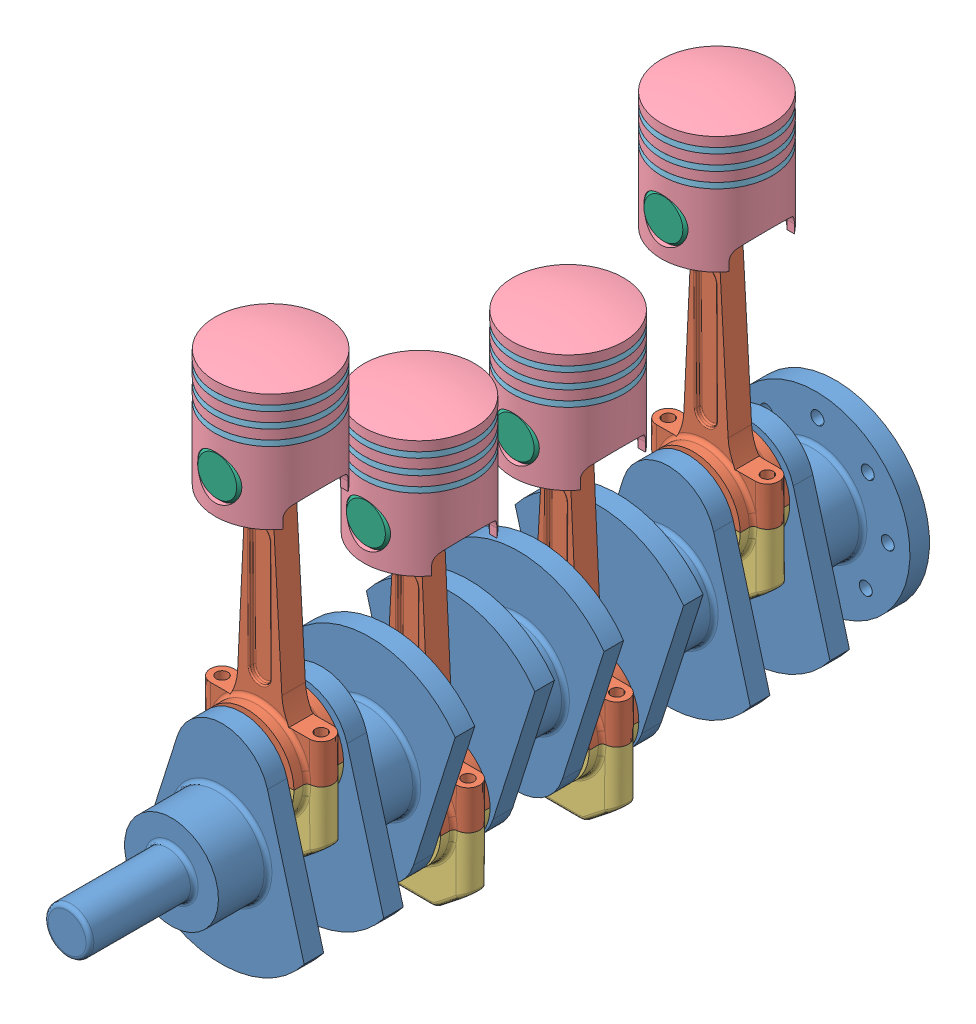
SolidWorks assembly Engine 2003083, configuration Default. Lengths in mm.
Overall size (147.06 418.41 589).
29 component instances, 6 part files, 66 mates.
Components (placement in the parent):
- Crankshaft-1: Crankshaft [Default] at (0 0 456) x (-0.999814 0.019293 0) z (0 0 1) size (144 160 589)
- Connecting rod-1: Connecting rod [Default] at (0 245.19 433) x (0.999991 0.004219 0) z (0 0 1) size (94 223.7 38)
- Connecting rod cap-1: Connecting rod cap [Default] at (0.8489 43.9918 433) x (-0.999991 -0.004219 0) z (0 0 1) size (94 60 38)
- Piston-1: Piston [Default] at (0 219.2199 433) size (85 95 85)
- Piston ring-1: Piston ring [Default] at (0 297.6199 433) size (85 4.3 85)
- Piston Pin-1: Piston Pin [Default] at (0 245.19 433) size (33.8 33.8 82)
- Piston ring-2: Piston ring [Default] at (0 286.0199 433) x (0.546944 0 -0.837169) z (0.837169 0 0.546944) size (85 4.3 85)
- Piston ring-4: Piston ring [Default] at (0 274.4199 433) x (0.546944 0 -0.837169) z (0.837169 0 0.546944) size (85 4.3 85)
- Piston-2: Piston [Default] at (0 131.2362 319) size (85 95 85)
- Piston ring-6: Piston ring [Default] at (0 209.6362 319) x (0.941458 0 -0.337131) z (0.337131 0 0.941458) size (85 4.3 85)
- Piston ring-7: Piston ring [Default] at (0 198.0362 319) x (0.23269 0 -0.972551) z (0.972551 0 0.23269) size (85 4.3 85)
- Piston ring-8: Piston ring [Default] at (0 186.4362 319) x (0.23269 0 -0.972551) z (0.972551 0 0.23269) size (85 4.3 85)
- Piston Pin-2: Piston Pin [Default] at (0 157.2064 319) x (0.216826 -0.97621 0) z (0 0 1) size (33.8 33.8 82)
- Connecting rod-2: Connecting rod [Default] at (0 157.2064 319) x (0.999991 -0.004219 0) z (0 0 1) size (94 223.7 38)
- Connecting rod cap-2: Connecting rod cap [Default] at (-0.8489 -43.9918 319) x (-0.999991 0.004219 0) z (0 0 1) size (94 60 38)
- Piston-4: Piston [Default] at (0 131.2362 205) x (-1 0 0) z (0 0 -1) size (85 95 85)
- Piston ring-12: Piston ring [Default] at (0 209.6362 205) x (0.790546 0 -0.612403) z (0.612403 0 0.790546) size (85 4.3 85)
- Piston ring-13: Piston ring [Default] at (0 198.0362 205) x (-0.0803 0 -0.996771) z (0.996771 0 -0.0803) size (85 4.3 85)
- Piston ring-14: Piston ring [Default] at (0 186.4362 205) x (-0.0803 0 -0.996771) z (0.996771 0 -0.0803) size (85 4.3 85)
- Piston Pin-4: Piston Pin [Default] at (0 157.2064 205) x (-0.34202 0.939693 0) z (0 0 -1) size (33.8 33.8 82)
- Connecting rod-4: Connecting rod [Default] at (0 157.2064 205) x (-0.999991 0.004219 0) z (0 0 -1) size (94 223.7 38)
- Connecting rod cap-4: Connecting rod cap [Default] at (-0.8489 -43.9918 205) x (0.999991 -0.004219 0) z (0 0 -1) size (94 60 38)
- Piston-6: Piston [Default] at (0 219.2199 91) x (-1 0 0) z (0 0 -1) size (85 95 85)
- Piston ring-18: Piston ring [Default] at (0 297.6199 91) x (0.6 0 -0.8) z (0.8 0 0.6) size (85 4.3 85)
- Piston ring-19: Piston ring [Default] at (0 286.0199 91) x (-0.341569 0 -0.939857) z (0.939857 0 -0.341569) size (85 4.3 85)
- Piston ring-20: Piston ring [Default] at (0 274.4199 91) x (-0.341569 0 -0.939857) z (0.939857 0 -0.341569) size (85 4.3 85)
- Piston Pin-6: Piston Pin [Default] at (0 245.19 91) x (-0.5 0.866025 0) z (0 0 -1) size (33.8 33.8 82)
- Connecting rod-6: Connecting rod [Default] at (0 245.19 91) x (-0.999991 -0.004219 0) z (0 0 -1) size (94 223.7 38)
- Connecting rod cap-6: Connecting rod cap [Default] at (0.8489 43.9918 91) x (0.999991 0.004219 0) z (0 0 -1) size (94 60 38)
Mates (geometry in assembly coordinates):
- Concentric1: concentric anti-aligned: cylinder of Crankshaft-1 through (0 0 589) axis (0 0 -1) radius 17.5
- Coincident1: coincident: plane of Crankshaft-1 through (0 0 589) normal (0 0 1)
- Coincident2: coincident aligned: plane of Piston-1 through (0 219.2199 433) normal (0 0 1); plane of Piston Pin-1 through (0 245.19 433) normal (0 0 1)
- Concentric2: concentric anti-aligned: cylinder of Piston-1 through (0 245.19 390.5) axis (0 0 1) radius 16.9; cylinder of Piston Pin-1 through (0 245.19 474) axis (0 0 -1) radius 16.9
- Concentric3: concentric aligned: cylinder of Piston-1 through (0 309.2199 433) axis (0 -1 0) radius 42.5; cylinder of Piston ring-1 through (0 301.9199 433) axis (0 -1 0) radius 42.5
- Coincident3: coincident anti-aligned: plane of Piston-1 through (0 297.6199 433) normal (0 1 0); plane of Piston ring-1 through (0 297.6199 433) normal (0 -1 0)
- Concentric4: concentric anti-aligned: cylinder of Piston-1 through (0 286.0199 433) axis (0 1 0) radius 39.5; cylinder of Piston ring-2 through (0 290.3199 433) axis (0 -1 0) radius 42.5
- Coincident4: coincident anti-aligned: plane of Piston-1 through (0 286.0199 433) normal (0 1 0); plane of Piston ring-2 through (0 286.0199 433) normal (0 -1 0)
- Concentric5: concentric anti-aligned: cylinder of Piston-1 through (0 274.4199 433) axis (0 1 0) radius 39.5; cylinder of Piston ring-4 through (0 278.7199 433) axis (0 -1 0) radius 42.5
- Coincident5: coincident anti-aligned: plane of Piston-1 through (0 274.4199 433) normal (0 1 0); plane of Piston ring-4 through (0 274.4199 433) normal (0 -1 0)
- Coincident6: coincident aligned: plane of Connecting rod-1 through (0 245.19 433) normal (0 0 1); plane of Piston-1 through (0 219.2199 433) normal (0 0 1)
- Concentric6: concentric aligned: cylinder of Connecting rod-1 through (0 245.19 452) axis (0 0 -1) radius 16.9; cylinder of Piston Pin-1 through (0 245.19 474) axis (0 0 -1) radius 16.9
- Concentric7: concentric aligned: cylinder of Connecting rod-1 through (38.8486 44.1521 433) axis (-0.004219 0.999991 0) radius 4.5; cylinder of Connecting rod cap-1 through (39.1017 -15.8473 433) axis (-0.004219 0.999991 0) radius 4.5
- Concentric8: concentric aligned: cylinder of Connecting rod-1 through (-37.1508 43.8315 433) axis (-0.004219 0.999991 0) radius 4.5; cylinder of Connecting rod cap-1 through (-36.8976 -16.168 433) axis (-0.004219 0.999991 0) radius 4.5
- Coincident7: coincident anti-aligned: plane of Connecting rod-1 through (0.8489 43.9918 452) normal (0.004219 -0.999991 0); plane of Connecting rod cap-1 through (36.8486 44.1437 452) normal (-0.004219 0.999991 0)
- Width1: width anti-aligned: plane of Crankshaft-1 through (0 0 410) normal (0 0 1); plane of Crankshaft-1 through (0 0 456) normal (0 0 -1); plane of Connecting rod-1 through (0 245.19 424) normal (0 0 -1); plane of Connecting rod-1 through (0 245.19 442) normal (0 0 1)
- Concentric9: concentric anti-aligned: cylinder of Crankshaft-1 through (0.8489 43.9918 410) axis (0 0 1) radius 27; cylinder of Connecting rod-1 through (0.8489 43.9918 452) axis (0 0 -1) radius 27
- Concentric10: concentric anti-aligned: cylinder of Piston-1 through (0 309.2199 433) axis (0 -1 0) radius 42.5
- Coincident9: coincident aligned: plane of Piston-2 through (0 131.2362 319) normal (0 0 1); plane of Piston Pin-2 through (0 157.2064 319) normal (0 0 1)
- Concentric11: concentric anti-aligned: cylinder of Piston-2 through (0 157.2064 276.5) axis (0 0 1) radius 16.9; cylinder of Piston Pin-2 through (0 157.2064 360) axis (0 0 -1) radius 16.9
- Concentric12: concentric aligned: cylinder of Piston-2 through (0 221.2362 319) axis (0 -1 0) radius 42.5; cylinder of Piston ring-6 through (0 213.9362 319) axis (0 -1 0) radius 42.5
- Coincident10: coincident anti-aligned: plane of Piston-2 through (0 209.6362 319) normal (0 1 0); plane of Piston ring-6 through (0 209.6362 319) normal (0 -1 0)
- Concentric13: concentric anti-aligned: cylinder of Piston-2 through (0 198.0362 319) axis (0 1 0) radius 39.5; cylinder of Piston ring-7 through (0 202.3362 319) axis (0 -1 0) radius 42.5
- Coincident11: coincident anti-aligned: plane of Piston-2 through (0 198.0362 319) normal (0 1 0); plane of Piston ring-7 through (0 198.0362 319) normal (0 -1 0)
- Concentric14: concentric anti-aligned: cylinder of Piston-2 through (0 186.4362 319) axis (0 1 0) radius 39.5; cylinder of Piston ring-8 through (0 190.7362 319) axis (0 -1 0) radius 42.5
- Coincident12: coincident anti-aligned: plane of Piston-2 through (0 186.4362 319) normal (0 1 0); plane of Piston ring-8 through (0 186.4362 319) normal (0 -1 0)
- Coincident13: coincident aligned: plane of Piston-2 through (0 131.2362 319) normal (0 0 1); plane of Connecting rod-2 through (0 157.2064 319) normal (0 0 1)
- Concentric15: concentric aligned: cylinder of Piston Pin-2 through (0 157.2064 360) axis (0 0 -1) radius 16.9; cylinder of Connecting rod-2 through (0 157.2064 338) axis (0 0 -1) radius 16.9
- Concentric16: concentric aligned: cylinder of Connecting rod-2 through (37.1508 -44.1521 319) axis (0.004219 0.999991 0) radius 4.5; cylinder of Connecting rod cap-2 through (36.8976 -104.1516 319) axis (0.004219 0.999991 0) radius 4.5
- Concentric17: concentric aligned: cylinder of Connecting rod-2 through (-38.8486 -43.8315 319) axis (0.004219 0.999991 0) radius 4.5; cylinder of Connecting rod cap-2 through (-39.1017 -103.8309 319) axis (0.004219 0.999991 0) radius 4.5
- Coincident14: coincident anti-aligned: plane of Connecting rod-2 through (-0.8489 -43.9918 338) normal (-0.004219 -0.999991 0); plane of Connecting rod cap-2 through (35.1508 -44.1437 338) normal (0.004219 0.999991 0)
- Width2: width anti-aligned: plane of Crankshaft-1 through (0 0 342) normal (0 0 -1); plane of Crankshaft-1 through (0 0 296) normal (0 0 1); plane of Connecting rod-2 through (0 157.2064 310) normal (0 0 -1); plane of Connecting rod-2 through (0 157.2064 328) normal (0 0 1)
- Concentric18: concentric anti-aligned: cylinder of Crankshaft-1 through (-0.8489 -43.9918 296) axis (0 0 1) radius 27; cylinder of Connecting rod-2 through (-0.8489 -43.9918 338) axis (0 0 -1) radius 27
- Concentric19: concentric anti-aligned: cylinder of Piston-2 through (0 221.2362 319) axis (0 -1 0) radius 42.5
- Coincident21: coincident aligned: plane of Piston-4 through (0 131.2362 205) normal (0 0 -1); plane of Piston Pin-4 through (0 157.2064 205) normal (0 0 -1)
- Concentric27: concentric anti-aligned: cylinder of Piston-4 through (0 157.2064 247.5) axis (0 0 -1) radius 16.9; cylinder of Piston Pin-4 through (0 157.2064 164) axis (0 0 1) radius 16.9
- Concentric28: concentric aligned: cylinder of Piston-4 through (0 221.2362 205) axis (0 -1 0) radius 42.5; cylinder of Piston ring-12 through (0 213.9362 205) axis (0 -1 0) radius 42.5
- Coincident22: coincident anti-aligned: plane of Piston-4 through (0 209.6362 205) normal (0 1 0); plane of Piston ring-12 through (0 209.6362 205) normal (0 -1 0)
- Concentric29: concentric anti-aligned: cylinder of Piston-4 through (0 198.0362 205) axis (0 1 0) radius 39.5; cylinder of Piston ring-13 through (0 202.3362 205) axis (0 -1 0) radius 42.5
- Coincident23: coincident anti-aligned: plane of Piston-4 through (0 198.0362 205) normal (0 1 0); plane of Piston ring-13 through (0 198.0362 205) normal (0 -1 0)
- Concentric30: concentric anti-aligned: cylinder of Piston-4 through (0 186.4362 205) axis (0 1 0) radius 39.5; cylinder of Piston ring-14 through (0 190.7362 205) axis (0 -1 0) radius 42.5
- Coincident24: coincident anti-aligned: plane of Piston-4 through (0 186.4362 205) normal (0 1 0); plane of Piston ring-14 through (0 186.4362 205) normal (0 -1 0)
- Coincident25: coincident aligned: plane of Piston-4 through (0 131.2362 205) normal (0 0 -1); plane of Connecting rod-4 through (0 157.2064 205) normal (0 0 -1)
- Concentric31: concentric aligned: cylinder of Piston Pin-4 through (0 157.2064 164) axis (0 0 1) radius 16.9; cylinder of Connecting rod-4 through (0 157.2064 186) axis (0 0 1) radius 16.9
- Concentric32: concentric aligned: cylinder of Connecting rod-4 through (-38.8486 -43.8315 205) axis (0.004219 0.999991 0) radius 4.5; cylinder of Connecting rod cap-4 through (-39.1017 -103.8309 205) axis (0.004219 0.999991 0) radius 4.5
- Concentric33: concentric aligned: cylinder of Connecting rod-4 through (37.1508 -44.1521 205) axis (0.004219 0.999991 0) radius 4.5; cylinder of Connecting rod cap-4 through (36.8976 -104.1516 205) axis (0.004219 0.999991 0) radius 4.5
- Coincident26: coincident anti-aligned: plane of Connecting rod-4 through (-0.8489 -43.9918 186) normal (-0.004219 -0.999991 0); plane of Connecting rod cap-4 through (-36.8486 -43.8399 186) normal (0.004219 0.999991 0)
- Width3: width anti-aligned: plane of Crankshaft-1 through (0 0 228) normal (0 0 -1); plane of Crankshaft-1 through (0 0 182) normal (0 0 1); plane of Connecting rod-4 through (0 157.2064 214) normal (0 0 1); plane of Connecting rod-4 through (0 157.2064 196) normal (0 0 -1)
- Concentric34: concentric anti-aligned: cylinder of Crankshaft-1 through (-0.8489 -43.9918 228) axis (0 0 -1) radius 27; cylinder of Connecting rod-4 through (-0.8489 -43.9918 186) axis (0 0 1) radius 27
- Concentric35: concentric anti-aligned: cylinder of Piston-4 through (0 221.2362 205) axis (0 -1 0) radius 42.5
- Coincident33: coincident aligned: plane of Piston-6 through (0 219.2199 91) normal (0 0 -1); plane of Piston Pin-6 through (0 245.19 91) normal (0 0 -1)
- Concentric43: concentric anti-aligned: cylinder of Piston-6 through (0 245.19 133.5) axis (0 0 -1) radius 16.9; cylinder of Piston Pin-6 through (0 245.19 50) axis (0 0 1) radius 16.9
- Concentric44: concentric aligned: cylinder of Piston-6 through (0 309.2199 91) axis (0 -1 0) radius 42.5; cylinder of Piston ring-18 through (0 301.9199 91) axis (0 -1 0) radius 42.5
- Coincident34: coincident anti-aligned: plane of Piston-6 through (0 297.6199 91) normal (0 1 0); plane of Piston ring-18 through (0 297.6199 91) normal (0 -1 0)
- Concentric45: concentric anti-aligned: cylinder of Piston-6 through (0 286.0199 91) axis (0 1 0) radius 39.5; cylinder of Piston ring-19 through (0 290.3199 91) axis (0 -1 0) radius 42.5
- Coincident35: coincident anti-aligned: plane of Piston-6 through (0 286.0199 91) normal (0 1 0); plane of Piston ring-19 through (0 286.0199 91) normal (0 -1 0)
- Concentric46: concentric anti-aligned: cylinder of Piston-6 through (0 274.4199 91) axis (0 1 0) radius 39.5; cylinder of Piston ring-20 through (0 278.7199 91) axis (0 -1 0) radius 42.5
- Coincident36: coincident anti-aligned: plane of Piston-6 through (0 274.4199 91) normal (0 1 0); plane of Piston ring-20 through (0 274.4199 91) normal (0 -1 0)
- Coincident37: coincident aligned: plane of Piston-6 through (0 219.2199 91) normal (0 0 -1); plane of Connecting rod-6 through (0 245.19 91) normal (0 0 -1)
- Concentric47: concentric aligned: cylinder of Piston Pin-6 through (0 245.19 50) axis (0 0 1) radius 16.9; cylinder of Connecting rod-6 through (0 245.19 72) axis (0 0 1) radius 16.9
- Concentric48: concentric aligned: cylinder of Connecting rod-6 through (-37.1508 43.8315 91) axis (-0.004219 0.999991 0) radius 4.5; cylinder of Connecting rod cap-6 through (-36.8976 -16.168 91) axis (-0.004219 0.999991 0) radius 4.5
- Concentric49: concentric aligned: cylinder of Connecting rod-6 through (38.8486 44.1521 91) axis (-0.004219 0.999991 0) radius 4.5; cylinder of Connecting rod cap-6 through (39.1017 -15.8473 91) axis (-0.004219 0.999991 0) radius 4.5
- Coincident38: coincident anti-aligned: plane of Connecting rod-6 through (0.8489 43.9918 72) normal (0.004219 -0.999991 0); plane of Connecting rod cap-6 through (-35.1508 43.8399 72) normal (-0.004219 0.999991 0)
- Width4: width anti-aligned: plane of Crankshaft-1 through (0 0 114) normal (0 0 -1); plane of Crankshaft-1 through (0 0 68) normal (0 0 1); plane of Connecting rod-6 through (0 245.19 100) normal (0 0 1); plane of Connecting rod-6 through (0 245.19 82) normal (0 0 -1)
- Concentric50: concentric anti-aligned: cylinder of Crankshaft-1 through (0.8489 43.9918 114) axis (0 0 -1) radius 27; cylinder of Connecting rod-6 through (0.8489 43.9918 72) axis (0 0 1) radius 27
- Concentric51: concentric anti-aligned: cylinder of Piston-6 through (0 309.2199 91) axis (0 -1 0) radius 42.5
